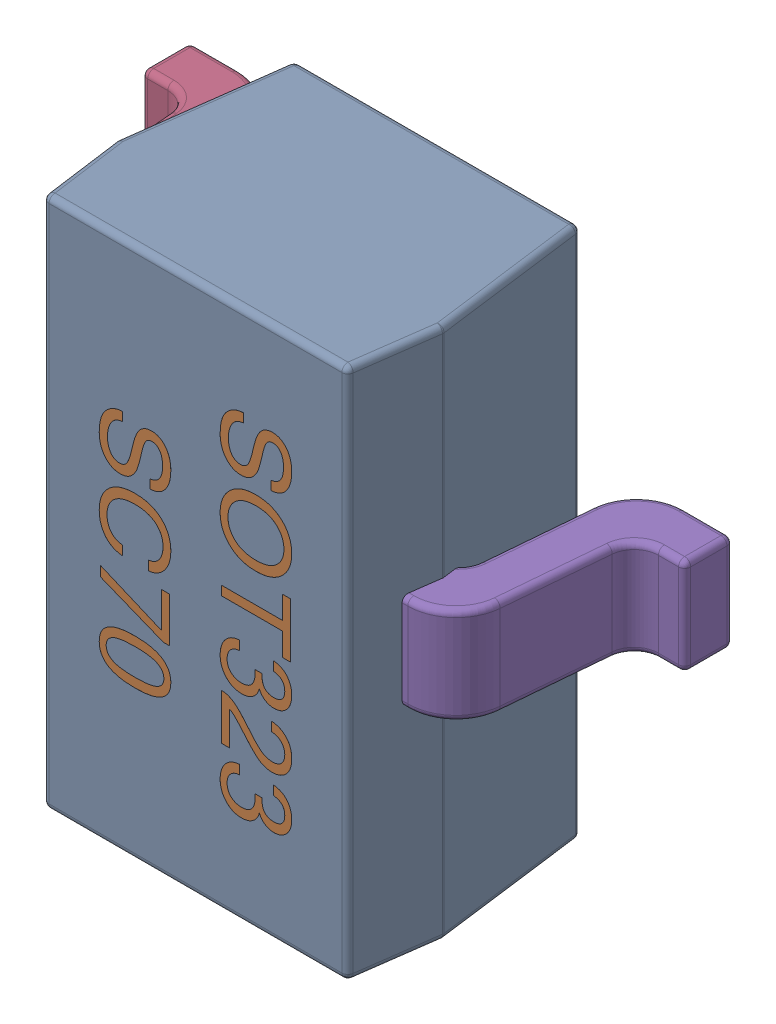
SolidWorks assembly Q1.step, configuration Default. Lengths in mm.
Overall size (2.25 2.2 1.1).
6 component instances, 3 part files, 0 mates.
Components (placement in the parent):
- SOT323_(SC70-3)-1.step-1: SOT323_(SC70-3)-1.step [Default] at (15.3671 35.8141 0) x (0 -1 0) z (-1 0 0) size (2.2 1.1 2.25)
  - User_Library-SOT323_(SC70-3)-1_K_X_F6rper_1.step-1: User_Library-SOT323_(SC70-3)-1_K_X_F6rper_1.step [Default] x (0 0 -1) z (0 1 0) size (1.35 2.2 1)
  - User_Library-SOT323_(SC70-3)-1_Beschriftung_1.step-1: User_Library-SOT323_(SC70-3)-1_Beschriftung_1.step [Default] x (0 0 -1) z (0 1 0) size (0.8 1.45 0.06)
  - User_Library-SOT323_(SC70-3)-1_Pins_1.step-1: User_Library-SOT323_(SC70-3)-1_Pins_1.step [Default] at (0.65 0 0) x (0 0 1) z (0 1 0) size (0.6 0.4 0.9)
  - User_Library-SOT323_(SC70-3)-1_Pins_1.step-2: User_Library-SOT323_(SC70-3)-1_Pins_1.step [Default] at (-0.65 0 0) x (0 0 1) z (0 1 0) size (0.6 0.4 0.9)
  - User_Library-SOT323_(SC70-3)-1_Pins_1.step-3: User_Library-SOT323_(SC70-3)-1_Pins_1.step [Default] x (0 0 -1) z (0 1 0) size (0.6 0.4 0.9)
